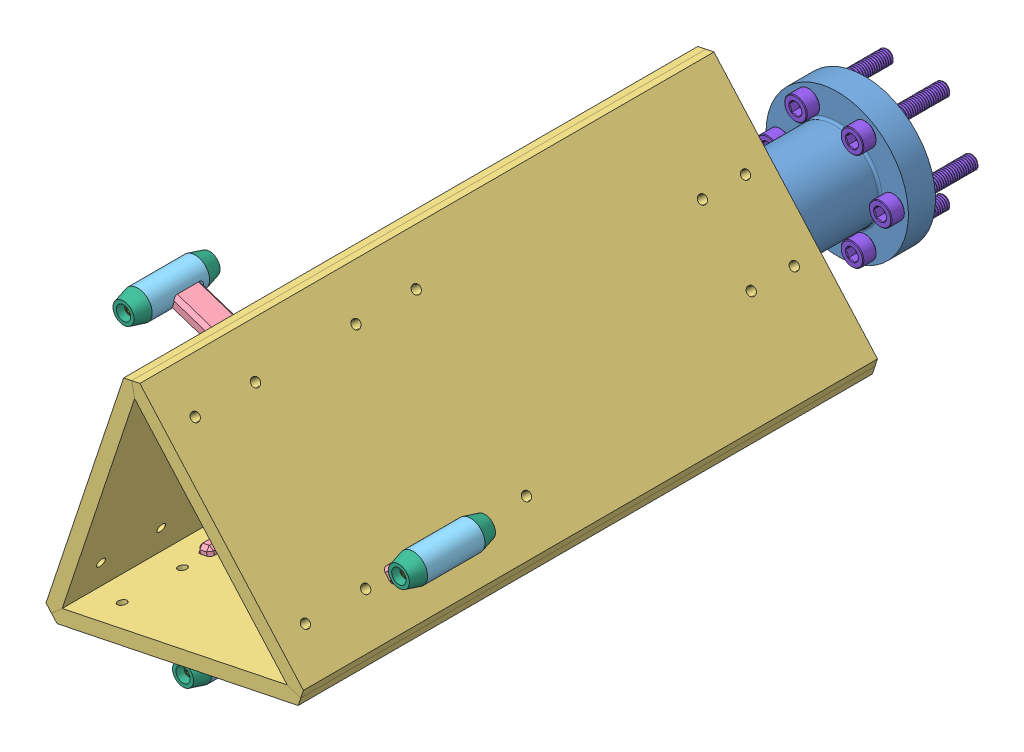
SolidWorks assembly Frame Assembly (FR), configuration Default. Lengths in mm.
Overall size (142.98 145.53 334.34).
32 component instances, 8 part files, 33 mates.
Components (placement in the parent):
- Mounting Shaft (FR-1)-1: Mounting Shaft (FR-1) [Default] at (1.4417 19.9516 -46.3155) size (63 63 76)
- Triangle (FR-2)-1: Triangle (FR-2) [Default] at (1.4417 19.9516 10.6845) x (0.979489 0.201496 0) z (0 0 1) size (101.6 87.99 6.35)
- Frame Plate (FR-3)-1: Frame Plate (FR-3) [Default] at (23.3658 39.4335 112.2845) x (0.664246 -0.747514 0) z (0.747514 0.664246 0) size (112.6 254 6.35)
- Frame Plate (FR-3)-2: Frame Plate (FR-3) [Default] at (-26.3922 29.1975 112.2845) x (0.315244 0.949011 0) z (-0.949011 0.315244 0) size (112.6 254 6.35)
- Frame Plate (FR-3)-3: Frame Plate (FR-3) [Default] at (7.3514 -8.7763 112.2845) x (-0.979489 -0.201496 0) z (0.201496 -0.979489 0) size (112.6 254 6.35)
- Bump Stop Assembly (BS)-1: Bump Stop Assembly (BS) [Default] at (-48.4512 43.2804 219.086) x (-0.315244 -0.949011 0) z (0.949011 -0.315244 0) size (14.59 38.1 45.39)
  - Bump Stop Bar (BS-1)-1: Bump Stop Bar (BS-1) [Default] at (-30.3388 9.583 -9.5512) size (6.22 12.57 38.1)
  - Bump Stop Rod (BS-2)-1: Bump Stop Rod (BS-2) [Default] at (-30.3388 18.7905 -9.5512) x (0 0 1) z (0 -1 0) size (12.7 12.7 25.4)
  - Bump Stop Bumper (MMC 9540K842)-1: Bump Stop Bumper (MMC 9540K842) [Default] at (-30.3388 18.7905 -9.5512) x (0.986856 0 -0.161605) z (0 1 0) size (12.7 12.7 6.35)
  - Bump Stop Bumper (MMC 9540K842)-2: Bump Stop Bumper (MMC 9540K842) [Default] at (-30.3388 -6.6095 -9.5512) x (1 0 0) z (0 -1 0) size (12.7 12.7 6.35)
  - Bump Stop Bolt (MMC 91306A256)-1: Bump Stop Bolt (MMC 91306A256) [91306A256] at (-30.3388 22.8482 -9.5512) x (1 0 0) z (0 1 0) size (6.05 6.05 8.36)
  - Bump Stop Bolt (MMC 91306A256)-2: Bump Stop Bolt (MMC 91306A256) [91306A256] at (-30.3388 -10.6671 -9.5512) x (1 0 0) z (0 -1 0) size (6.05 6.05 8.36)
- Bump Stop Assembly (BS)-2: Bump Stop Assembly (BS) [Default] at (46.5915 51.4956 219.086) x (-0.664246 0.747514 0) z (-0.747514 -0.664246 0) size (14.59 38.1 45.39)
  - Bump Stop Bar (BS-1)-1: Bump Stop Bar (BS-1) [Default] at (-30.3388 9.583 -9.5512) size (6.22 12.57 38.1)
  - Bump Stop Rod (BS-2)-1: Bump Stop Rod (BS-2) [Default] at (-30.3388 18.7905 -9.5512) x (0 0 1) z (0 -1 0) size (12.7 12.7 25.4)
  - Bump Stop Bumper (MMC 9540K842)-1: Bump Stop Bumper (MMC 9540K842) [Default] at (-30.3388 18.7905 -9.5512) x (0.986856 0 -0.161605) z (0 1 0) size (12.7 12.7 6.35)
  - Bump Stop Bumper (MMC 9540K842)-2: Bump Stop Bumper (MMC 9540K842) [Default] at (-30.3388 -6.6095 -9.5512) x (1 0 0) z (0 -1 0) size (12.7 12.7 6.35)
  - Bump Stop Bolt (MMC 91306A256)-1: Bump Stop Bolt (MMC 91306A256) [91306A256] at (-30.3388 22.8482 -9.5512) x (1 0 0) z (0 1 0) size (6.05 6.05 8.36)
  - Bump Stop Bolt (MMC 91306A256)-2: Bump Stop Bolt (MMC 91306A256) [91306A256] at (-30.3388 -10.6671 -9.5512) x (1 0 0) z (0 -1 0) size (6.05 6.05 8.36)
- Bump Stop Assembly (BS)-3: Bump Stop Assembly (BS) [Default] at (6.1847 -34.9214 219.086) x (0.979489 0.201496 0) z (-0.201496 0.979489 0) size (14.59 38.1 45.39)
  - Bump Stop Bar (BS-1)-1: Bump Stop Bar (BS-1) [Default] at (-30.3388 9.583 -9.5512) size (6.22 12.57 38.1)
  - Bump Stop Rod (BS-2)-1: Bump Stop Rod (BS-2) [Default] at (-30.3388 18.7905 -9.5512) x (0 0 1) z (0 -1 0) size (12.7 12.7 25.4)
  - Bump Stop Bumper (MMC 9540K842)-1: Bump Stop Bumper (MMC 9540K842) [Default] at (-30.3388 18.7905 -9.5512) x (0.986856 0 -0.161605) z (0 1 0) size (12.7 12.7 6.35)
  - Bump Stop Bumper (MMC 9540K842)-2: Bump Stop Bumper (MMC 9540K842) [Default] at (-30.3388 -6.6095 -9.5512) x (1 0 0) z (0 -1 0) size (12.7 12.7 6.35)
  - Bump Stop Bolt (MMC 91306A256)-1: Bump Stop Bolt (MMC 91306A256) [91306A256] at (-30.3388 22.8482 -9.5512) x (1 0 0) z (0 1 0) size (6.05 6.05 8.36)
  - Bump Stop Bolt (MMC 91306A256)-2: Bump Stop Bolt (MMC 91306A256) [91306A256] at (-30.3388 -10.6671 -9.5512) x (1 0 0) z (0 -1 0) size (6.05 6.05 8.36)
- Bolt Circle Bolts (MMC 91290A334)-1: Bolt Circle Bolts (MMC 91290A334) [91290A334] at (26.4417 19.9516 -69.3155) x (-0.923728 -0.383049 0) z (0 0 -1) size (10 10 41.63)
- Bolt Circle Bolts (MMC 91290A334)-2: Bolt Circle Bolts (MMC 91290A334) [91290A334] at (-23.5583 19.9516 -69.3155) x (-0.923728 -0.383049 0) z (0 0 -1) size (10 10 41.63)
- Bolt Circle Bolts (MMC 91290A334)-3: Bolt Circle Bolts (MMC 91290A334) [91290A334] at (-11.0583 41.6022 -69.3155) x (-0.923728 -0.383049 0) z (0 0 -1) size (10 10 41.63)
- Bolt Circle Bolts (MMC 91290A334)-4: Bolt Circle Bolts (MMC 91290A334) [91290A334] at (-11.0583 -1.6991 -69.3155) x (-0.923728 -0.383049 0) z (0 0 -1) size (10 10 41.63)
- Bolt Circle Bolts (MMC 91290A334)-5: Bolt Circle Bolts (MMC 91290A334) [91290A334] at (13.9417 -1.6991 -69.3155) x (-0.923728 -0.383049 0) z (0 0 -1) size (10 10 41.63)
- Bolt Circle Bolts (MMC 91290A334)-6: Bolt Circle Bolts (MMC 91290A334) [91290A334] at (13.9417 41.6022 -69.3155) x (-0.923728 -0.383049 0) z (0 0 -1) size (10 10 41.63)
Mates (geometry in assembly coordinates):
- Concentric1: concentric anti-aligned: cylinder of Mounting Shaft (FR-1)-1 through (1.4417 19.9516 23.6845) axis (0 0 -1) radius 16.9375; cylinder of Triangle (FR-2)-1 through (1.4417 19.9516 10.6845) axis (0 0 1) radius 17.4625
- Coincident1: coincident anti-aligned: plane of Mounting Shaft (FR-1)-1 through (1.4417 19.9516 10.6845) normal (0 0 1); plane of Triangle (FR-2)-1 through (1.4417 19.9516 10.6845) normal (0 0 -1)
- Lock1: lock: unknown of Mounting Shaft (FR-1)-1; unknown of Triangle (FR-2)-1
- Coincident2: coincident anti-aligned: plane of Triangle (FR-2)-1 through (57.1095 1.4597 17.0345) normal (0.747514 0.664246 0); plane of Frame Plate (FR-3)-1 through (23.3658 39.4335 112.2845) normal (-0.747514 -0.664246 0)
- Coincident3: coincident aligned: plane of Triangle (FR-2)-1 through (1.4417 19.9516 10.6845) normal (0 0 -1); plane of Frame Plate (FR-3)-1 through (-5.6311 81.6252 10.6845) normal (0 0 -1)
- Coincident6: coincident aligned: line of Triangle (FR-2)-1 through (57.1095 1.4597 17.0345) axis (0 0 -1); line of Frame Plate (FR-3)-1 through (57.1095 1.4597 264.6845) axis (0 0 -1)
- Coincident7: coincident anti-aligned: plane of Triangle (FR-2)-1 through (-10.3779 77.4072 17.0345) normal (-0.949011 0.315244 0); plane of Frame Plate (FR-3)-2 through (-26.3922 29.1975 112.2845) normal (0.949011 -0.315244 0)
- Coincident8: coincident aligned: plane of Triangle (FR-2)-1 through (1.4417 19.9516 10.6845) normal (0 0 -1); plane of Frame Plate (FR-3)-2 through (-48.4328 -17.0105 10.6845) normal (0 0 -1)
- Coincident9: coincident anti-aligned: line of Triangle (FR-2)-1 through (-42.4066 -19.0123 17.0345) axis (0 0 -1); line of Frame Plate (FR-3)-2 through (-42.4066 -19.0123 10.6845) axis (0 0 1)
- Coincident10: coincident anti-aligned: plane of Triangle (FR-2)-1 through (-42.4066 -19.0123 17.0345) normal (0.201496 -0.979489 0); plane of Frame Plate (FR-3)-3 through (7.3514 -8.7763 112.2845) normal (-0.201496 0.979489 0)
- Coincident11: coincident aligned: plane of Triangle (FR-2)-1 through (1.4417 19.9516 10.6845) normal (0 0 -1); plane of Frame Plate (FR-3)-3 through (58.389 -4.76 10.6845) normal (0 0 -1)
- Coincident12: coincident anti-aligned: line of Frame Plate (FR-3)-2 through (-42.4066 -19.0123 10.6845) axis (0 0 1); line of Frame Plate (FR-3)-3 through (-42.4066 -19.0123 264.6845) axis (0 0 -1)
- Distance4: distance = 0.127 mm anti-aligned: plane of Frame Plate (FR-3)-2 through (-13.7862 67.1467 215.7895) normal (-0.315244 -0.949011 0); plane of Bump Stop Assembly (BS)-1/Bump Stop Bar (BS-1)-1 through (-10.8131 66.0252 215.7895) normal (0.315244 0.949011 0)
- Distance3: distance = 0.127 mm anti-aligned: plane of Frame Plate (FR-3)-2 through (-15.788 61.1204 203.0895) normal (0 0 1); plane of Bump Stop Assembly (BS)-1/Bump Stop Bar (BS-1)-1 through (-10.8131 66.0252 203.2165) normal (0 0 -1)
- Distance2: distance = 3.175 mm aligned: plane of Bump Stop Assembly (BS)-1/Bump Stop Bar (BS-1)-1 through (-11.794 63.0724 209.503) normal (0.949011 -0.315244 0); plane of Frame Plate (FR-3)-2 through (-26.3922 29.1975 112.2845) normal (0.949011 -0.315244 0)
- Distance5: distance = 0.127 mm anti-aligned: plane of Frame Plate (FR-3)-1 through (49.9278 9.5417 215.7895) normal (-0.664246 0.747514 0); plane of Bump Stop Assembly (BS)-2/Bump Stop Bar (BS-1)-1 through (47.4701 7.5277 215.7895) normal (0.664246 -0.747514 0)
- Distance6: distance = 0.127 mm anti-aligned: plane of Bump Stop Assembly (BS)-2/Bump Stop Bar (BS-1)-1 through (47.4701 7.5277 203.2165) normal (0 0 -1); plane of Frame Plate (FR-3)-1 through (45.7098 14.2885 203.0895) normal (0 0 1)
- Distance7: distance = 3.175 mm aligned: plane of Bump Stop Assembly (BS)-2/Bump Stop Bar (BS-1)-1 through (45.4033 9.8536 209.503) normal (-0.747514 -0.664246 0); plane of Frame Plate (FR-3)-1 through (23.3658 39.4335 112.2845) normal (-0.747514 -0.664246 0)
- Distance8: distance = 0.127 mm anti-aligned: plane of Frame Plate (FR-3)-3 through (-31.8165 -16.8337 215.7895) normal (0.979489 0.201496 0); plane of Bump Stop Assembly (BS)-3/Bump Stop Bar (BS-1)-1 through (-32.3319 -13.6983 215.7895) normal (-0.979489 -0.201496 0)
- Distance9: distance = 0.127 mm anti-aligned: plane of Bump Stop Assembly (BS)-3/Bump Stop Bar (BS-1)-1 through (-32.3319 -13.6983 203.2165) normal (0 0 -1); plane of Frame Plate (FR-3)-3 through (-25.5968 -15.5542 203.0895) normal (0 0 1)
- Distance10: distance = 3.175 mm aligned: plane of Bump Stop Assembly (BS)-3/Bump Stop Bar (BS-1)-1 through (-29.2842 -13.0713 209.503) normal (-0.201496 0.979489 0); plane of Frame Plate (FR-3)-3 through (7.3514 -8.7763 112.2845) normal (-0.201496 0.979489 0)
- Concentric2: concentric anti-aligned: cylinder of Mounting Shaft (FR-1)-1 through (26.4417 19.9516 -34.3155) axis (0 0 1) radius 3.25; cylinder of Bolt Circle Bolts (MMC 91290A334)-1 through (26.4417 19.9516 -28.3155) axis (0 0 -1) radius 5
- Coincident13: coincident anti-aligned: plane of Mounting Shaft (FR-1)-1 through (1.4417 19.9516 -34.3155) normal (0 0 1); plane of Bolt Circle Bolts (MMC 91290A334)-1 through (26.4417 19.9516 -34.3155) normal (0 0 -1)
- Concentric3: concentric anti-aligned: cylinder of Mounting Shaft (FR-1)-1 through (13.9417 41.6022 -34.3155) axis (0 0 1) radius 3.25; cylinder of Bolt Circle Bolts (MMC 91290A334)-6 through (13.9417 41.6022 -28.3155) axis (0 0 -1) radius 5
- Coincident14: coincident anti-aligned: plane of Mounting Shaft (FR-1)-1 through (1.4417 19.9516 -34.3155) normal (0 0 1); plane of Bolt Circle Bolts (MMC 91290A334)-6 through (13.9417 41.6022 -34.3155) normal (0 0 -1)
- Concentric4: concentric anti-aligned: cylinder of Mounting Shaft (FR-1)-1 through (-11.0583 41.6022 -34.3155) axis (0 0 1) radius 3.25; cylinder of Bolt Circle Bolts (MMC 91290A334)-3 through (-11.0583 41.6022 -28.3155) axis (0 0 -1) radius 5
- Coincident15: coincident anti-aligned: plane of Mounting Shaft (FR-1)-1 through (1.4417 19.9516 -34.3155) normal (0 0 1); plane of Bolt Circle Bolts (MMC 91290A334)-3 through (-11.0583 41.6022 -34.3155) normal (0 0 -1)
- Concentric5: concentric anti-aligned: cylinder of Mounting Shaft (FR-1)-1 through (-23.5583 19.9516 -34.3155) axis (0 0 1) radius 3.25; cylinder of Bolt Circle Bolts (MMC 91290A334)-2 through (-23.5583 19.9516 -28.3155) axis (0 0 -1) radius 5
- Coincident16: coincident anti-aligned: plane of Mounting Shaft (FR-1)-1 through (1.4417 19.9516 -34.3155) normal (0 0 1); plane of Bolt Circle Bolts (MMC 91290A334)-2 through (-23.5583 19.9516 -34.3155) normal (0 0 -1)
- Concentric6: concentric anti-aligned: cylinder of Mounting Shaft (FR-1)-1 through (-11.0583 -1.6991 -34.3155) axis (0 0 1) radius 3.25; cylinder of Bolt Circle Bolts (MMC 91290A334)-4 through (-11.0583 -1.6991 -28.3155) axis (0 0 -1) radius 5
- Coincident17: coincident anti-aligned: plane of Mounting Shaft (FR-1)-1 through (1.4417 19.9516 -34.3155) normal (0 0 1); plane of Bolt Circle Bolts (MMC 91290A334)-4 through (-11.0583 -1.6991 -34.3155) normal (0 0 -1)
- Concentric7: concentric anti-aligned: cylinder of Mounting Shaft (FR-1)-1 through (13.9417 -1.6991 -34.3155) axis (0 0 1) radius 3.25; cylinder of Bolt Circle Bolts (MMC 91290A334)-5 through (13.9417 -1.6991 -28.3155) axis (0 0 -1) radius 5
- Coincident18: coincident anti-aligned: plane of Mounting Shaft (FR-1)-1 through (1.4417 19.9516 -34.3155) normal (0 0 1); plane of Bolt Circle Bolts (MMC 91290A334)-5 through (13.9417 -1.6991 -34.3155) normal (0 0 -1)
